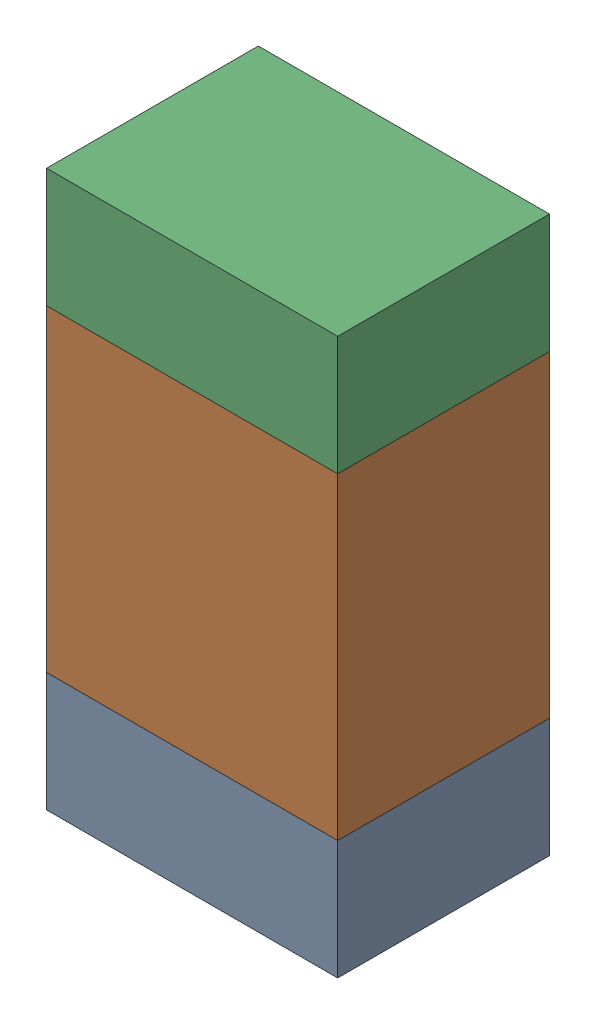
SolidWorks assembly R113_2PCB, configuration Default. Lengths in mm.
Overall size (0.55 1.05 0.4).
6 component instances, 2 part files, 0 mates.
Components (placement in the parent):
- 846483288-1: 846483288 [Default] at (115.6999 87.5876 0) size (0.55 0.22 0.4)
  - Extruded_12-1: Extruded_12 [Default] at origin size (0.55 0.22 0.4)
- 846483424-1: 846483424 [Default] at (115.6999 88.0001 0) size (0.55 0.6 0.4)
  - Extruded_13-1: Extruded_13 [Default] at origin size (0.55 0.6 0.4)
- 846483288-2: 846483288 [Default] at (115.6999 88.4126 0) size (0.55 0.22 0.4)
  - Extruded_12-1: Extruded_12 [Default] at origin size (0.55 0.22 0.4)
